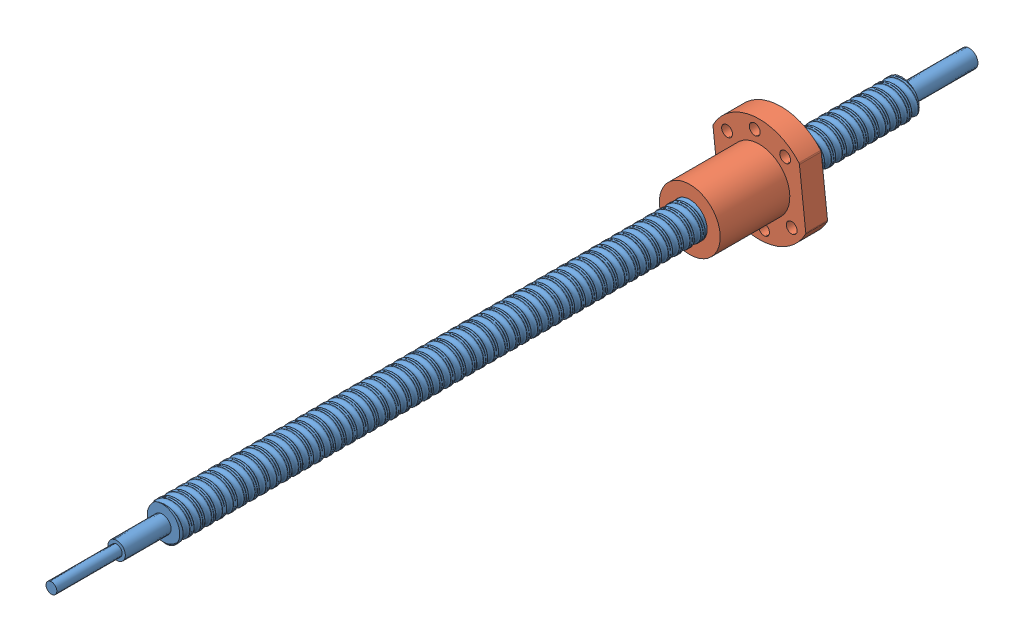
SolidWorks assembly X-axis screw assembly, configuration Default. Lengths in mm.
Overall size (45.12 52.17 422).
2 component instances, 2 part files, 2 mates.
Components (placement in the parent):
- X-axis ball screw-1: X-axis ball screw [Default] at (158.7458 201.5294 381.7583) size (16.21 16.21 422)
- X-axis ball screw nut-1: X-axis ball screw nut [Default] at (158.7458 201.5294 437.2734) x (-0.99372 -0.111898 0) z (0 0 -1) size (40 48 42)
Mates (geometry in assembly coordinates):
- Concentric1: concentric aligned: cylinder of X-axis ball screw-1 through (158.7458 201.5294 742.7583) axis (0 0 -1) radius 4; cylinder of X-axis ball screw nut-1 through (158.7458 201.5294 479.2734) axis (0 0 -1) radius 14
- Screw1: screw = 5 mm aligned: cylinder of X-axis ball screw-1 through (158.7458 201.5294 742.7583) axis (0 0 -1) radius 4; cylinder of X-axis ball screw nut-1 through (158.7458 201.5294 479.2734) axis (0 0 -1) radius 14
